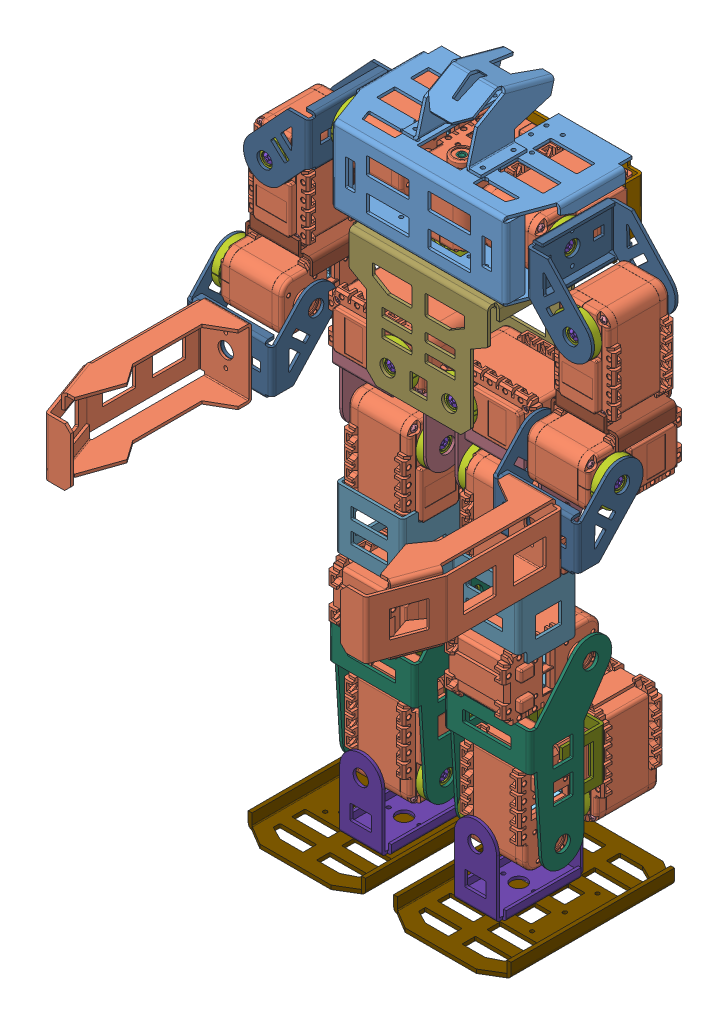
SolidWorks assembly BioloidGP2, configuration Default. Lengths in mm.
Overall size (259 352.56 195.51).
245 component instances, 20 part files, 109 mates.
Components (placement in the parent):
- FR04-E120-1: FR04-E120 [Default] at (-6.1822 -2.1819 114.2456) size (106 40.5 61.5)
- AX-12-18-A-2: AX-12-18-A [Default] at (31.961 8.8095 126.4932) x (0 1 0) z (1 0 0) size (32 50.04 40.18)
  - ASM0002_ASM-1: ASM0002_ASM [Default] at (-10.9914 -11.7476 -2.6432) size (32 50.04 40.18)
    - PRT0001-1: PRT0001 [Default] at origin size (32 50.04 38.06)
    - PRT0002-1: PRT0002 [Default] at (0 0 -2) x (-1 0 0) z (0 0 1) size (6.5 6.5 5.5)
    - PRT0003-1: PRT0003 [Default] at (9.5 8.5 14.5) x (-1 0 0) z (0 1 0) size (3.6 31.47 4.83)
    - PRT0003-2: PRT0003 [Default] at (-9.5 8.5 14.5) x (-1 0 0) z (0 1 0) size (3.6 31.47 4.83)
    - PRT0003-3: PRT0003 [Default] at (10.5 -33 14.5) x (-1 0 0) z (0 1 0) size (3.6 31.47 4.83)
    - PRT0003-4: PRT0003 [Default] at (-10.5 -33 14.5) x (-1 0 0) z (0 1 0) size (3.6 31.47 4.83)
    - PRT0004-1: PRT0004 [Default] at (5.05 -15.19 -9.75) x (1 0 0) z (0 1 0) size (9.9 9.43 4.9)
    - PRT0004-2: PRT0004 [Default] at (-4.95 -15.19 -9.75) x (1 0 0) z (0 1 0) size (9.9 9.43 4.9)
    - PRT0005-1: PRT0005 [Default] at (0 0 -18.4) x (-1 0 0) z (0 1 0) size (4.98 7 4.98)
    - PRT0006-1: PRT0006 [Default] at (0 0 19.16) x (0 1 0) z (0 0 1) size (22 22 6.7)
    - PRT0007-1: PRT0007 [Default] at (0 0 19.48) x (-1 0 0) z (0 1 0) size (5.5 9.69 5.91)
- AX-12-18-A-4: AX-12-18-A [Default] at (-44.3255 -13.1733 126.4932) x (0 -1 0) z (-1 0 0) size (32 50.04 40.18)
  - ASM0002_ASM-1: ASM0002_ASM [Default] at (-10.9914 -11.7476 -2.6432) size (32 50.04 40.18)
    - PRT0001-1: PRT0001 [Default] at origin size (32 50.04 38.06)
    - PRT0002-1: PRT0002 [Default] at (0 0 -2) x (-1 0 0) z (0 0 1) size (6.5 6.5 5.5)
    - PRT0003-1: PRT0003 [Default] at (9.5 8.5 14.5) x (-1 0 0) z (0 1 0) size (3.6 31.47 4.83)
    - PRT0003-2: PRT0003 [Default] at (-9.5 8.5 14.5) x (-1 0 0) z (0 1 0) size (3.6 31.47 4.83)
    - PRT0003-3: PRT0003 [Default] at (10.5 -33 14.5) x (-1 0 0) z (0 1 0) size (3.6 31.47 4.83)
    - PRT0003-4: PRT0003 [Default] at (-10.5 -33 14.5) x (-1 0 0) z (0 1 0) size (3.6 31.47 4.83)
    - PRT0004-1: PRT0004 [Default] at (5.05 -15.19 -9.75) x (1 0 0) z (0 1 0) size (9.9 9.43 4.9)
    - PRT0004-2: PRT0004 [Default] at (-4.95 -15.19 -9.75) x (1 0 0) z (0 1 0) size (9.9 9.43 4.9)
    - PRT0005-1: PRT0005 [Default] at (0 0 -18.4) x (-1 0 0) z (0 1 0) size (4.98 7 4.98)
    - PRT0006-1: PRT0006 [Default] at (0 0 19.16) x (0 1 0) z (0 0 1) size (22 22 6.7)
    - PRT0007-1: PRT0007 [Default] at (0 0 19.48) x (-1 0 0) z (0 1 0) size (5.5 9.69 5.91)
- FR04-E150-1: FR04-E150 [Default] at (-6.1822 -2.1819 115.0456) size (106 53 9.7)
- AX-12-18-A-6: AX-12-18-A [Default] at (4.8092 -10.3251 125.9932) x (1 0 0) z (0 -1 0) size (32 50.04 40.18)
  - ASM0002_ASM-1: ASM0002_ASM [Default] at (-10.9914 -11.7476 -2.6432) size (32 50.04 40.18)
    - PRT0001-1: PRT0001 [Default] at origin size (32 50.04 38.06)
    - PRT0002-1: PRT0002 [Default] at (0 0 -2) x (-1 0 0) z (0 0 1) size (6.5 6.5 5.5)
    - PRT0003-1: PRT0003 [Default] at (9.5 8.5 14.5) x (-1 0 0) z (0 1 0) size (3.6 31.47 4.83)
    - PRT0003-2: PRT0003 [Default] at (-9.5 8.5 14.5) x (-1 0 0) z (0 1 0) size (3.6 31.47 4.83)
    - PRT0003-3: PRT0003 [Default] at (10.5 -33 14.5) x (-1 0 0) z (0 1 0) size (3.6 31.47 4.83)
    - PRT0003-4: PRT0003 [Default] at (-10.5 -33 14.5) x (-1 0 0) z (0 1 0) size (3.6 31.47 4.83)
    - PRT0004-1: PRT0004 [Default] at (5.05 -15.19 -9.75) x (1 0 0) z (0 1 0) size (9.9 9.43 4.9)
    - PRT0004-2: PRT0004 [Default] at (-4.95 -15.19 -9.75) x (1 0 0) z (0 1 0) size (9.9 9.43 4.9)
    - PRT0005-1: PRT0005 [Default] at (0 0 -18.4) x (-1 0 0) z (0 1 0) size (4.98 7 4.98)
    - PRT0006-1: PRT0006 [Default] at (0 0 19.16) x (0 1 0) z (0 0 1) size (22 22 6.7)
    - PRT0007-1: PRT0007 [Default] at (0 0 19.48) x (-1 0 0) z (0 1 0) size (5.5 9.69 5.91)
- FR04-H102-1: FR04-H102 [Default] at (73.3178 -20.1819 114.7456) x (0 0 1) z (0 -1 0) size (45.02 34.01 42)
- FR04-H102-2: FR04-H102 [Default] at (-85.6822 -20.1819 114.7456) x (0 0 -1) z (0 -1 0) size (45.02 34.01 42)
- AX-12-18-A-7: AX-12-18-A [Default] at (84.3092 -8.4342 117.3888) size (32 50.04 40.18)
  - ASM0002_ASM-1: ASM0002_ASM [Default] at (-10.9914 -11.7476 -2.6432) size (32 50.04 40.18)
    - PRT0001-1: PRT0001 [Default] at origin size (32 50.04 38.06)
    - PRT0002-1: PRT0002 [Default] at (0 0 -2) x (-1 0 0) z (0 0 1) size (6.5 6.5 5.5)
    - PRT0003-1: PRT0003 [Default] at (9.5 8.5 14.5) x (-1 0 0) z (0 1 0) size (3.6 31.47 4.83)
    - PRT0003-2: PRT0003 [Default] at (-9.5 8.5 14.5) x (-1 0 0) z (0 1 0) size (3.6 31.47 4.83)
    - PRT0003-3: PRT0003 [Default] at (10.5 -33 14.5) x (-1 0 0) z (0 1 0) size (3.6 31.47 4.83)
    - PRT0003-4: PRT0003 [Default] at (-10.5 -33 14.5) x (-1 0 0) z (0 1 0) size (3.6 31.47 4.83)
    - PRT0004-1: PRT0004 [Default] at (5.05 -15.19 -9.75) x (1 0 0) z (0 1 0) size (9.9 9.43 4.9)
    - PRT0004-2: PRT0004 [Default] at (-4.95 -15.19 -9.75) x (1 0 0) z (0 1 0) size (9.9 9.43 4.9)
    - PRT0005-1: PRT0005 [Default] at (0 0 -18.4) x (-1 0 0) z (0 1 0) size (4.98 7 4.98)
    - PRT0006-1: PRT0006 [Default] at (0 0 19.16) x (0 1 0) z (0 0 1) size (22 22 6.7)
    - PRT0007-1: PRT0007 [Default] at (0 0 19.48) x (-1 0 0) z (0 1 0) size (5.5 9.69 5.91)
- AX-12-18-A-8: AX-12-18-A [Default] at (-74.6908 -8.4342 117.3888) size (32 50.04 40.18)
  - ASM0002_ASM-1: ASM0002_ASM [Default] at (-10.9914 -11.7476 -2.6432) size (32 50.04 40.18)
    - PRT0001-1: PRT0001 [Default] at origin size (32 50.04 38.06)
    - PRT0002-1: PRT0002 [Default] at (0 0 -2) x (-1 0 0) z (0 0 1) size (6.5 6.5 5.5)
    - PRT0003-1: PRT0003 [Default] at (9.5 8.5 14.5) x (-1 0 0) z (0 1 0) size (3.6 31.47 4.83)
    - PRT0003-2: PRT0003 [Default] at (-9.5 8.5 14.5) x (-1 0 0) z (0 1 0) size (3.6 31.47 4.83)
    - PRT0003-3: PRT0003 [Default] at (10.5 -33 14.5) x (-1 0 0) z (0 1 0) size (3.6 31.47 4.83)
    - PRT0003-4: PRT0003 [Default] at (-10.5 -33 14.5) x (-1 0 0) z (0 1 0) size (3.6 31.47 4.83)
    - PRT0004-1: PRT0004 [Default] at (5.05 -15.19 -9.75) x (1 0 0) z (0 1 0) size (9.9 9.43 4.9)
    - PRT0004-2: PRT0004 [Default] at (-4.95 -15.19 -9.75) x (1 0 0) z (0 1 0) size (9.9 9.43 4.9)
    - PRT0005-1: PRT0005 [Default] at (0 0 -18.4) x (-1 0 0) z (0 1 0) size (4.98 7 4.98)
    - PRT0006-1: PRT0006 [Default] at (0 0 19.16) x (0 1 0) z (0 0 1) size (22 22 6.7)
    - PRT0007-1: PRT0007 [Default] at (0 0 19.48) x (-1 0 0) z (0 1 0) size (5.5 9.69 5.91)
- AX-12-18-A-9: AX-12-18-A [Default] at (75.961 -66.5905 144.6932) x (0 1 0) z (1 0 0) size (32 50.04 40.18)
  - ASM0002_ASM-1: ASM0002_ASM [Default] at (-10.9914 -11.7476 -2.6432) size (32 50.04 40.18)
    - PRT0001-1: PRT0001 [Default] at origin size (32 50.04 38.06)
    - PRT0002-1: PRT0002 [Default] at (0 0 -2) x (-1 0 0) z (0 0 1) size (6.5 6.5 5.5)
    - PRT0003-1: PRT0003 [Default] at (9.5 8.5 14.5) x (-1 0 0) z (0 1 0) size (3.6 31.47 4.83)
    - PRT0003-2: PRT0003 [Default] at (-9.5 8.5 14.5) x (-1 0 0) z (0 1 0) size (3.6 31.47 4.83)
    - PRT0003-3: PRT0003 [Default] at (10.5 -33 14.5) x (-1 0 0) z (0 1 0) size (3.6 31.47 4.83)
    - PRT0003-4: PRT0003 [Default] at (-10.5 -33 14.5) x (-1 0 0) z (0 1 0) size (3.6 31.47 4.83)
    - PRT0004-1: PRT0004 [Default] at (5.05 -15.19 -9.75) x (1 0 0) z (0 1 0) size (9.9 9.43 4.9)
    - PRT0004-2: PRT0004 [Default] at (-4.95 -15.19 -9.75) x (1 0 0) z (0 1 0) size (9.9 9.43 4.9)
    - PRT0005-1: PRT0005 [Default] at (0 0 -18.4) x (-1 0 0) z (0 1 0) size (4.98 7 4.98)
    - PRT0006-1: PRT0006 [Default] at (0 0 19.16) x (0 1 0) z (0 0 1) size (22 22 6.7)
    - PRT0007-1: PRT0007 [Default] at (0 0 19.48) x (-1 0 0) z (0 1 0) size (5.5 9.69 5.91)
- AX-12-18-A-10: AX-12-18-A [Default] at (-88.3255 -88.5733 144.6932) x (0 -1 0) z (-1 0 0) size (32 50.04 40.18)
  - ASM0002_ASM-1: ASM0002_ASM [Default] at (-10.9914 -11.7476 -2.6432) size (32 50.04 40.18)
    - PRT0001-1: PRT0001 [Default] at origin size (32 50.04 38.06)
    - PRT0002-1: PRT0002 [Default] at (0 0 -2) x (-1 0 0) z (0 0 1) size (6.5 6.5 5.5)
    - PRT0003-1: PRT0003 [Default] at (9.5 8.5 14.5) x (-1 0 0) z (0 1 0) size (3.6 31.47 4.83)
    - PRT0003-2: PRT0003 [Default] at (-9.5 8.5 14.5) x (-1 0 0) z (0 1 0) size (3.6 31.47 4.83)
    - PRT0003-3: PRT0003 [Default] at (10.5 -33 14.5) x (-1 0 0) z (0 1 0) size (3.6 31.47 4.83)
    - PRT0003-4: PRT0003 [Default] at (-10.5 -33 14.5) x (-1 0 0) z (0 1 0) size (3.6 31.47 4.83)
    - PRT0004-1: PRT0004 [Default] at (5.05 -15.19 -9.75) x (1 0 0) z (0 1 0) size (9.9 9.43 4.9)
    - PRT0004-2: PRT0004 [Default] at (-4.95 -15.19 -9.75) x (1 0 0) z (0 1 0) size (9.9 9.43 4.9)
    - PRT0005-1: PRT0005 [Default] at (0 0 -18.4) x (-1 0 0) z (0 1 0) size (4.98 7 4.98)
    - PRT0006-1: PRT0006 [Default] at (0 0 19.16) x (0 1 0) z (0 0 1) size (22 22 6.7)
    - PRT0007-1: PRT0007 [Default] at (0 0 19.48) x (-1 0 0) z (0 1 0) size (5.5 9.69 5.91)
- FR04-SC101-3: FR04-SC101 [Default] at (-85.6822 -59.3819 114.7456) size (35 14.9 35)
- FR04-SC101-4: FR04-SC101 [Default] at (73.3178 -59.3819 114.7456) size (35 14.9 35)
- FR04-H102-3: FR04-H102 [Default] at (-85.6822 -77.5819 132.9456) x (-1 0 0) z (0 1 0) size (45.02 34.01 42)
- FR04-H102-4: FR04-H102 [Default] at (73.3178 -77.5819 132.9456) x (-1 0 0) z (0 1 0) size (45.02 34.01 42)
- FR04-E131-1: FR04-E131 [Default] at (-6.1822 -82.1819 114.2456) size (76 64.5 45)
- AX-12-18-A-11: AX-12-18-A [Default] at (-1.9298 -71.1905 116.8888) x (0 1 0) z (0 0 1) size (32 50.04 40.18)
  - ASM0002_ASM-1: ASM0002_ASM [Default] at (-10.9914 -11.7476 -2.6432) size (32 50.04 40.18)
    - PRT0001-1: PRT0001 [Default] at origin size (32 50.04 38.06)
    - PRT0002-1: PRT0002 [Default] at (0 0 -2) x (-1 0 0) z (0 0 1) size (6.5 6.5 5.5)
    - PRT0003-1: PRT0003 [Default] at (9.5 8.5 14.5) x (-1 0 0) z (0 1 0) size (3.6 31.47 4.83)
    - PRT0003-2: PRT0003 [Default] at (-9.5 8.5 14.5) x (-1 0 0) z (0 1 0) size (3.6 31.47 4.83)
    - PRT0003-3: PRT0003 [Default] at (10.5 -33 14.5) x (-1 0 0) z (0 1 0) size (3.6 31.47 4.83)
    - PRT0003-4: PRT0003 [Default] at (-10.5 -33 14.5) x (-1 0 0) z (0 1 0) size (3.6 31.47 4.83)
    - PRT0004-1: PRT0004 [Default] at (5.05 -15.19 -9.75) x (1 0 0) z (0 1 0) size (9.9 9.43 4.9)
    - PRT0004-2: PRT0004 [Default] at (-4.95 -15.19 -9.75) x (1 0 0) z (0 1 0) size (9.9 9.43 4.9)
    - PRT0005-1: PRT0005 [Default] at (0 0 -18.4) x (-1 0 0) z (0 1 0) size (4.98 7 4.98)
    - PRT0006-1: PRT0006 [Default] at (0 0 19.16) x (0 1 0) z (0 0 1) size (22 22 6.7)
    - PRT0007-1: PRT0007 [Default] at (0 0 19.48) x (-1 0 0) z (0 1 0) size (5.5 9.69 5.91)
- AX-12-18-A-13: AX-12-18-A [Default] at (-10.4346 -93.1733 116.8888) x (0 -1 0) z (0 0 1) size (32 50.04 40.18)
  - ASM0002_ASM-1: ASM0002_ASM [Default] at (-10.9914 -11.7476 -2.6432) size (32 50.04 40.18)
    - PRT0001-1: PRT0001 [Default] at origin size (32 50.04 38.06)
    - PRT0002-1: PRT0002 [Default] at (0 0 -2) x (-1 0 0) z (0 0 1) size (6.5 6.5 5.5)
    - PRT0003-1: PRT0003 [Default] at (9.5 8.5 14.5) x (-1 0 0) z (0 1 0) size (3.6 31.47 4.83)
    - PRT0003-2: PRT0003 [Default] at (-9.5 8.5 14.5) x (-1 0 0) z (0 1 0) size (3.6 31.47 4.83)
    - PRT0003-3: PRT0003 [Default] at (10.5 -33 14.5) x (-1 0 0) z (0 1 0) size (3.6 31.47 4.83)
    - PRT0003-4: PRT0003 [Default] at (-10.5 -33 14.5) x (-1 0 0) z (0 1 0) size (3.6 31.47 4.83)
    - PRT0004-1: PRT0004 [Default] at (5.05 -15.19 -9.75) x (1 0 0) z (0 1 0) size (9.9 9.43 4.9)
    - PRT0004-2: PRT0004 [Default] at (-4.95 -15.19 -9.75) x (1 0 0) z (0 1 0) size (9.9 9.43 4.9)
    - PRT0005-1: PRT0005 [Default] at (0 0 -18.4) x (-1 0 0) z (0 1 0) size (4.98 7 4.98)
    - PRT0006-1: PRT0006 [Default] at (0 0 19.16) x (0 1 0) z (0 0 1) size (22 22 6.7)
    - PRT0007-1: PRT0007 [Default] at (0 0 19.48) x (-1 0 0) z (0 1 0) size (5.5 9.69 5.91)
- FR04-HC110-1: FR04-HC110 [Default] at (-36.1822 -123.9819 114.2456) size (45 42.8 35)
- FR04-HC110-2: FR04-HC110 [Default] at (23.8178 -123.9819 114.2456) x (-1 0 0) z (0 0 -1) size (45 42.8 35)
- AX-12-18-A-16: AX-12-18-A [Default] at (21.1745 -112.2342 125.237) x (0 0 1) z (-1 0 0) size (32 50.04 40.18)
  - ASM0002_ASM-1: ASM0002_ASM [Default] at (-10.9914 -11.7476 -2.6432) size (32 50.04 40.18)
    - PRT0001-1: PRT0001 [Default] at origin size (32 50.04 38.06)
    - PRT0002-1: PRT0002 [Default] at (0 0 -2) x (-1 0 0) z (0 0 1) size (6.5 6.5 5.5)
    - PRT0003-1: PRT0003 [Default] at (9.5 8.5 14.5) x (-1 0 0) z (0 1 0) size (3.6 31.47 4.83)
    - PRT0003-2: PRT0003 [Default] at (-9.5 8.5 14.5) x (-1 0 0) z (0 1 0) size (3.6 31.47 4.83)
    - PRT0003-3: PRT0003 [Default] at (10.5 -33 14.5) x (-1 0 0) z (0 1 0) size (3.6 31.47 4.83)
    - PRT0003-4: PRT0003 [Default] at (-10.5 -33 14.5) x (-1 0 0) z (0 1 0) size (3.6 31.47 4.83)
    - PRT0004-1: PRT0004 [Default] at (5.05 -15.19 -9.75) x (1 0 0) z (0 1 0) size (9.9 9.43 4.9)
    - PRT0004-2: PRT0004 [Default] at (-4.95 -15.19 -9.75) x (1 0 0) z (0 1 0) size (9.9 9.43 4.9)
    - PRT0005-1: PRT0005 [Default] at (0 0 -18.4) x (-1 0 0) z (0 1 0) size (4.98 7 4.98)
    - PRT0006-1: PRT0006 [Default] at (0 0 19.16) x (0 1 0) z (0 0 1) size (22 22 6.7)
    - PRT0007-1: PRT0007 [Default] at (0 0 19.48) x (-1 0 0) z (0 1 0) size (5.5 9.69 5.91)
- AX-12-18-A-17: AX-12-18-A [Default] at (-33.539 -112.2342 103.2542) x (0 0 -1) z (1 0 0) size (32 50.04 40.18)
  - ASM0002_ASM-1: ASM0002_ASM [Default] at (-10.9914 -11.7476 -2.6432) size (32 50.04 40.18)
    - PRT0001-1: PRT0001 [Default] at origin size (32 50.04 38.06)
    - PRT0002-1: PRT0002 [Default] at (0 0 -2) x (-1 0 0) z (0 0 1) size (6.5 6.5 5.5)
    - PRT0003-1: PRT0003 [Default] at (9.5 8.5 14.5) x (-1 0 0) z (0 1 0) size (3.6 31.47 4.83)
    - PRT0003-2: PRT0003 [Default] at (-9.5 8.5 14.5) x (-1 0 0) z (0 1 0) size (3.6 31.47 4.83)
    - PRT0003-3: PRT0003 [Default] at (10.5 -33 14.5) x (-1 0 0) z (0 1 0) size (3.6 31.47 4.83)
    - PRT0003-4: PRT0003 [Default] at (-10.5 -33 14.5) x (-1 0 0) z (0 1 0) size (3.6 31.47 4.83)
    - PRT0004-1: PRT0004 [Default] at (5.05 -15.19 -9.75) x (1 0 0) z (0 1 0) size (9.9 9.43 4.9)
    - PRT0004-2: PRT0004 [Default] at (-4.95 -15.19 -9.75) x (1 0 0) z (0 1 0) size (9.9 9.43 4.9)
    - PRT0005-1: PRT0005 [Default] at (0 0 -18.4) x (-1 0 0) z (0 1 0) size (4.98 7 4.98)
    - PRT0006-1: PRT0006 [Default] at (0 0 19.16) x (0 1 0) z (0 0 1) size (22 22 6.7)
    - PRT0007-1: PRT0007 [Default] at (0 0 19.48) x (-1 0 0) z (0 1 0) size (5.5 9.69 5.91)
- FR04-SC110-1: FR04-SC110 [Default] at (-36.1822 -123.6819 113.9456) size (35 37.2 29.5)
- FR04-SC110-2: FR04-SC110 [Default] at (23.8178 -123.6819 113.9456) size (35 37.2 29.5)
- AX-12-18-A-18: AX-12-18-A [Default] at (21.1745 -187.3905 87.9979) x (0 1 0) z (-1 0 0) size (32 50.04 40.18)
  - ASM0002_ASM-1: ASM0002_ASM [Default] at (-10.9914 -11.7476 -2.6432) size (32 50.04 40.18)
    - PRT0001-1: PRT0001 [Default] at origin size (32 50.04 38.06)
    - PRT0002-1: PRT0002 [Default] at (0 0 -2) x (-1 0 0) z (0 0 1) size (6.5 6.5 5.5)
    - PRT0003-1: PRT0003 [Default] at (9.5 8.5 14.5) x (-1 0 0) z (0 1 0) size (3.6 31.47 4.83)
    - PRT0003-2: PRT0003 [Default] at (-9.5 8.5 14.5) x (-1 0 0) z (0 1 0) size (3.6 31.47 4.83)
    - PRT0003-3: PRT0003 [Default] at (10.5 -33 14.5) x (-1 0 0) z (0 1 0) size (3.6 31.47 4.83)
    - PRT0003-4: PRT0003 [Default] at (-10.5 -33 14.5) x (-1 0 0) z (0 1 0) size (3.6 31.47 4.83)
    - PRT0004-1: PRT0004 [Default] at (5.05 -15.19 -9.75) x (1 0 0) z (0 1 0) size (9.9 9.43 4.9)
    - PRT0004-2: PRT0004 [Default] at (-4.95 -15.19 -9.75) x (1 0 0) z (0 1 0) size (9.9 9.43 4.9)
    - PRT0005-1: PRT0005 [Default] at (0 0 -18.4) x (-1 0 0) z (0 1 0) size (4.98 7 4.98)
    - PRT0006-1: PRT0006 [Default] at (0 0 19.16) x (0 1 0) z (0 0 1) size (22 22 6.7)
    - PRT0007-1: PRT0007 [Default] at (0 0 19.48) x (-1 0 0) z (0 1 0) size (5.5 9.69 5.91)
- AX-12-18-A-19: AX-12-18-A [Default] at (-33.539 -209.3733 87.9979) x (0 -1 0) z (1 0 0) size (32 50.04 40.18)
  - ASM0002_ASM-1: ASM0002_ASM [Default] at (-10.9914 -11.7476 -2.6432) size (32 50.04 40.18)
    - PRT0001-1: PRT0001 [Default] at origin size (32 50.04 38.06)
    - PRT0002-1: PRT0002 [Default] at (0 0 -2) x (-1 0 0) z (0 0 1) size (6.5 6.5 5.5)
    - PRT0003-1: PRT0003 [Default] at (9.5 8.5 14.5) x (-1 0 0) z (0 1 0) size (3.6 31.47 4.83)
    - PRT0003-2: PRT0003 [Default] at (-9.5 8.5 14.5) x (-1 0 0) z (0 1 0) size (3.6 31.47 4.83)
    - PRT0003-3: PRT0003 [Default] at (10.5 -33 14.5) x (-1 0 0) z (0 1 0) size (3.6 31.47 4.83)
    - PRT0003-4: PRT0003 [Default] at (-10.5 -33 14.5) x (-1 0 0) z (0 1 0) size (3.6 31.47 4.83)
    - PRT0004-1: PRT0004 [Default] at (5.05 -15.19 -9.75) x (1 0 0) z (0 1 0) size (9.9 9.43 4.9)
    - PRT0004-2: PRT0004 [Default] at (-4.95 -15.19 -9.75) x (1 0 0) z (0 1 0) size (9.9 9.43 4.9)
    - PRT0005-1: PRT0005 [Default] at (0 0 -18.4) x (-1 0 0) z (0 1 0) size (4.98 7 4.98)
    - PRT0006-1: PRT0006 [Default] at (0 0 19.16) x (0 1 0) z (0 0 1) size (22 22 6.7)
    - PRT0007-1: PRT0007 [Default] at (0 0 19.48) x (-1 0 0) z (0 1 0) size (5.5 9.69 5.91)
- FR04-H120-1: FR04-H120 [Default] at (-36.1822 -273.3819 114.2456) x (-1 0 0) z (0 0 1) size (45 97 42.5)
- FR04-H120-2: FR04-H120 [Default] at (23.8178 -273.3819 114.2456) x (-1 0 0) z (0 0 1) size (45 97 42.5)
- AX-12-18-A-20: AX-12-18-A [Default] at (-33.539 -285.1295 125.237) x (0 0 1) z (1 0 0) size (32 50.04 40.18)
  - ASM0002_ASM-1: ASM0002_ASM [Default] at (-10.9914 -11.7476 -2.6432) size (32 50.04 40.18)
    - PRT0001-1: PRT0001 [Default] at origin size (32 50.04 38.06)
    - PRT0002-1: PRT0002 [Default] at (0 0 -2) x (-1 0 0) z (0 0 1) size (6.5 6.5 5.5)
    - PRT0003-1: PRT0003 [Default] at (9.5 8.5 14.5) x (-1 0 0) z (0 1 0) size (3.6 31.47 4.83)
    - PRT0003-2: PRT0003 [Default] at (-9.5 8.5 14.5) x (-1 0 0) z (0 1 0) size (3.6 31.47 4.83)
    - PRT0003-3: PRT0003 [Default] at (10.5 -33 14.5) x (-1 0 0) z (0 1 0) size (3.6 31.47 4.83)
    - PRT0003-4: PRT0003 [Default] at (-10.5 -33 14.5) x (-1 0 0) z (0 1 0) size (3.6 31.47 4.83)
    - PRT0004-1: PRT0004 [Default] at (5.05 -15.19 -9.75) x (1 0 0) z (0 1 0) size (9.9 9.43 4.9)
    - PRT0004-2: PRT0004 [Default] at (-4.95 -15.19 -9.75) x (1 0 0) z (0 1 0) size (9.9 9.43 4.9)
    - PRT0005-1: PRT0005 [Default] at (0 0 -18.4) x (-1 0 0) z (0 1 0) size (4.98 7 4.98)
    - PRT0006-1: PRT0006 [Default] at (0 0 19.16) x (0 1 0) z (0 0 1) size (22 22 6.7)
    - PRT0007-1: PRT0007 [Default] at (0 0 19.48) x (-1 0 0) z (0 1 0) size (5.5 9.69 5.91)
- AX-12-18-A-21: AX-12-18-A [Default] at (21.1745 -285.1295 103.2542) x (0 0 -1) z (-1 0 0) size (32 50.04 40.18)
  - ASM0002_ASM-1: ASM0002_ASM [Default] at (-10.9914 -11.7476 -2.6432) size (32 50.04 40.18)
    - PRT0001-1: PRT0001 [Default] at origin size (32 50.04 38.06)
    - PRT0002-1: PRT0002 [Default] at (0 0 -2) x (-1 0 0) z (0 0 1) size (6.5 6.5 5.5)
    - PRT0003-1: PRT0003 [Default] at (9.5 8.5 14.5) x (-1 0 0) z (0 1 0) size (3.6 31.47 4.83)
    - PRT0003-2: PRT0003 [Default] at (-9.5 8.5 14.5) x (-1 0 0) z (0 1 0) size (3.6 31.47 4.83)
    - PRT0003-3: PRT0003 [Default] at (10.5 -33 14.5) x (-1 0 0) z (0 1 0) size (3.6 31.47 4.83)
    - PRT0003-4: PRT0003 [Default] at (-10.5 -33 14.5) x (-1 0 0) z (0 1 0) size (3.6 31.47 4.83)
    - PRT0004-1: PRT0004 [Default] at (5.05 -15.19 -9.75) x (1 0 0) z (0 1 0) size (9.9 9.43 4.9)
    - PRT0004-2: PRT0004 [Default] at (-4.95 -15.19 -9.75) x (1 0 0) z (0 1 0) size (9.9 9.43 4.9)
    - PRT0005-1: PRT0005 [Default] at (0 0 -18.4) x (-1 0 0) z (0 1 0) size (4.98 7 4.98)
    - PRT0006-1: PRT0006 [Default] at (0 0 19.16) x (0 1 0) z (0 0 1) size (22 22 6.7)
    - PRT0007-1: PRT0007 [Default] at (0 0 19.48) x (-1 0 0) z (0 1 0) size (5.5 9.69 5.91)
- FR04-X101-1: FR04-X101 [Default] at (-36.1822 -251.1819 100.9456) x (1 0 0) z (0 1 0) size (35 22.5 26.5)
- FR04-X101-2: FR04-X101 [Default] at (23.8178 -251.1819 100.9456) x (1 0 0) z (0 1 0) size (35 22.5 26.5)
- AX-12-18-A-22: AX-12-18-A [Default] at (-46.9736 -285.2295 73.5888) x (-1 0 0) z (0 0 1) size (32 50.04 40.18)
  - ASM0002_ASM-1: ASM0002_ASM [Default] at (-10.9914 -11.7476 -2.6432) size (32 50.04 40.18)
    - PRT0001-1: PRT0001 [Default] at origin size (32 50.04 38.06)
    - PRT0002-1: PRT0002 [Default] at (0 0 -2) x (-1 0 0) z (0 0 1) size (6.5 6.5 5.5)
    - PRT0003-1: PRT0003 [Default] at (9.5 8.5 14.5) x (-1 0 0) z (0 1 0) size (3.6 31.47 4.83)
    - PRT0003-2: PRT0003 [Default] at (-9.5 8.5 14.5) x (-1 0 0) z (0 1 0) size (3.6 31.47 4.83)
    - PRT0003-3: PRT0003 [Default] at (10.5 -33 14.5) x (-1 0 0) z (0 1 0) size (3.6 31.47 4.83)
    - PRT0003-4: PRT0003 [Default] at (-10.5 -33 14.5) x (-1 0 0) z (0 1 0) size (3.6 31.47 4.83)
    - PRT0004-1: PRT0004 [Default] at (5.05 -15.19 -9.75) x (1 0 0) z (0 1 0) size (9.9 9.43 4.9)
    - PRT0004-2: PRT0004 [Default] at (-4.95 -15.19 -9.75) x (1 0 0) z (0 1 0) size (9.9 9.43 4.9)
    - PRT0005-1: PRT0005 [Default] at (0 0 -18.4) x (-1 0 0) z (0 1 0) size (4.98 7 4.98)
    - PRT0006-1: PRT0006 [Default] at (0 0 19.16) x (0 1 0) z (0 0 1) size (22 22 6.7)
    - PRT0007-1: PRT0007 [Default] at (0 0 19.48) x (-1 0 0) z (0 1 0) size (5.5 9.69 5.91)
- AX-12-18-A-23: AX-12-18-A [Default] at (12.6264 -285.2295 73.5888) x (-1 0 0) z (0 0 1) size (32 50.04 40.18)
  - ASM0002_ASM-1: ASM0002_ASM [Default] at (-10.9914 -11.7476 -2.6432) size (32 50.04 40.18)
    - PRT0001-1: PRT0001 [Default] at origin size (32 50.04 38.06)
    - PRT0002-1: PRT0002 [Default] at (0 0 -2) x (-1 0 0) z (0 0 1) size (6.5 6.5 5.5)
    - PRT0003-1: PRT0003 [Default] at (9.5 8.5 14.5) x (-1 0 0) z (0 1 0) size (3.6 31.47 4.83)
    - PRT0003-2: PRT0003 [Default] at (-9.5 8.5 14.5) x (-1 0 0) z (0 1 0) size (3.6 31.47 4.83)
    - PRT0003-3: PRT0003 [Default] at (10.5 -33 14.5) x (-1 0 0) z (0 1 0) size (3.6 31.47 4.83)
    - PRT0003-4: PRT0003 [Default] at (-10.5 -33 14.5) x (-1 0 0) z (0 1 0) size (3.6 31.47 4.83)
    - PRT0004-1: PRT0004 [Default] at (5.05 -15.19 -9.75) x (1 0 0) z (0 1 0) size (9.9 9.43 4.9)
    - PRT0004-2: PRT0004 [Default] at (-4.95 -15.19 -9.75) x (1 0 0) z (0 1 0) size (9.9 9.43 4.9)
    - PRT0005-1: PRT0005 [Default] at (0 0 -18.4) x (-1 0 0) z (0 1 0) size (4.98 7 4.98)
    - PRT0006-1: PRT0006 [Default] at (0 0 19.16) x (0 1 0) z (0 0 1) size (22 22 6.7)
    - PRT0007-1: PRT0007 [Default] at (0 0 19.48) x (-1 0 0) z (0 1 0) size (5.5 9.69 5.91)
- FR04-H101-1: FR04-H101 [Default] at (-35.9822 -273.4819 114.4456) x (0 0 1) z (1 0 0) size (45 41 26)
- FR04-H101-2: FR04-H101 [Default] at (23.6178 -273.4819 114.4456) x (0 0 -1) z (-1 0 0) size (45 41 26)
- FR04-E160-1: FR04-E160 [Default] at (-43.9822 -303.4819 114.4456) size (61 8 97)
- FR04-E160-2: FR04-E160 [Default] at (31.6178 -303.4819 114.4456) size (61 8 97)
- FR04-E175-1: FR04-E175 [Default] at (-6.1822 15.3181 124.7294) x (1 0 0) z (0 0.258819 0.965926) size (41 31.63 43.12)
- FR04-E180-1: FR04-E180 [Default] at (-85.6822 -95.5819 155.9456) x (1 0 0) z (0 1 0) size (27 91.51 36)
- FR04-E180-2: FR04-E180 [Default] at (73.3178 -95.5819 155.9456) x (-1 0 0) z (0 -1 0) size (27 91.51 36)
Mates (geometry in assembly coordinates):
- Coincident2: coincident anti-aligned: plane of FR04-E120-1 through (45.3178 -2.1819 114.2456) normal (-1 0 0); plane of AX-12-18-A-2/ASM0002_ASM-1/PRT0001-1 through (45.3178 -2.1819 114.7456) normal (1 0 0)
- Coincident4: coincident anti-aligned: plane of FR04-E120-1 through (-59.2222 13.8181 135.9356) normal (0 -1 0); plane of AX-12-18-A-2/ASM0002_ASM-1/PRT0001-1 through (45.3178 13.8181 112.7456) normal (0 1 0)
- Coincident6: coincident anti-aligned: plane of FR04-E120-1 through (-57.6822 -2.1819 114.2456) normal (1 0 0); plane of AX-12-18-A-4/ASM0002_ASM-1/PRT0001-1 through (-57.6822 -2.1819 114.7456) normal (-1 0 0)
- Coincident7: coincident anti-aligned: plane of FR04-E120-1 through (-59.2222 13.8181 135.9356) normal (0 -1 0); plane of AX-12-18-A-4/ASM0002_ASM-1/PRT0001-1 through (-57.6822 13.8181 79.7456) normal (0 1 0)
- Coincident8: coincident anti-aligned: plane of FR04-E120-1 through (-59.2222 13.8181 135.9356) normal (0 -1 0); plane of FR04-E150-1 through (-6.1822 13.8181 115.0456) normal (0 1 0)
- Coincident9: coincident anti-aligned: plane of FR04-E120-1 through (-59.2222 -23.6819 74.0556) normal (0 1 0); plane of AX-12-18-A-6/ASM0002_ASM-1/PRT0001-1 through (-6.1822 -23.6819 114.2456) normal (0 -1 0)
- Coincident10: coincident anti-aligned: plane of FR04-E120-1 through (-6.1822 -2.1819 82.2456) normal (0 0 -1); plane of FR04-E150-1 through (-6.1822 -2.1819 82.2456) normal (0 0 1)
- Coincident11: coincident aligned: plane of FR04-E120-1 through (46.8178 -2.1819 114.2456) normal (1 0 0); plane of FR04-E150-1 through (46.8178 8.0181 82.2456) normal (1 0 0)
- Coincident12: coincident anti-aligned: plane of AX-12-18-A-2/ASM0002_ASM-1/PRT0001-1 through (48.3178 7.8181 82.2456) normal (0 0 -1); plane of FR04-E150-1 through (-6.1822 -2.1819 82.2456) normal (0 0 1)
- Coincident13: coincident anti-aligned: plane of AX-12-18-A-4/ASM0002_ASM-1/PRT0001-1 through (-60.6822 -12.1819 82.2456) normal (0 0 -1); plane of FR04-E150-1 through (-6.1822 -2.1819 82.2456) normal (0 0 1)
- Coincident14: coincident anti-aligned: plane of AX-12-18-A-2/ASM0002_ASM-1/PRT0006-1 through (50.3178 -2.1819 114.7456) normal (1 0 0); plane of FR04-H102-1 through (50.3178 9.7781 93.4256) normal (-1 0 0)
- Concentric1: concentric aligned: cylinder of AX-12-18-A-2/ASM0002_ASM-1/PRT0006-1 through (51.1778 -2.1819 114.7456) axis (1 0 0) radius 2.9; cylinder of FR04-H102-1 through (51.8178 -2.1819 114.7456) axis (1 0 0) radius 4
- Coincident15: coincident anti-aligned: plane of AX-12-18-A-4/ASM0002_ASM-1/PRT0006-1 through (-62.6822 -2.1819 114.7456) normal (-1 0 0); plane of FR04-H102-2 through (-62.6822 9.7781 136.0656) normal (1 0 0)
- Concentric2: concentric aligned: cylinder of AX-12-18-A-4/ASM0002_ASM-1/PRT0006-1 through (-63.5422 -2.1819 114.7456) axis (-1 0 0) radius 2.9; cylinder of FR04-H102-2 through (-64.1822 -2.1819 114.7456) axis (-1 0 0) radius 4
- Coincident16: coincident anti-aligned: plane of FR04-H102-1 through (51.6778 9.6181 135.7456) normal (0 0 -1); plane of AX-12-18-A-7/ASM0002_ASM-1/PRT0006-1 through (73.3178 -20.1819 135.7456) normal (0 0 1)
- Concentric3: concentric anti-aligned: cylinder of FR04-H102-1 through (73.3178 -20.1819 135.7456) axis (0 0 -1) radius 4; cylinder of AX-12-18-A-7/ASM0002_ASM-1/PRT0006-1 through (73.3178 -20.1819 136.6056) axis (0 0 1) radius 2.9
- Coincident18: coincident anti-aligned: plane of FR04-H102-2 through (-97.3232 9.6181 135.7456) normal (0 0 -1); plane of AX-12-18-A-8/ASM0002_ASM-1/PRT0006-1 through (-85.6822 -20.1819 135.7456) normal (0 0 1)
- Concentric4: concentric anti-aligned: cylinder of FR04-H102-2 through (-85.6822 -20.1819 135.7456) axis (0 0 -1) radius 4; cylinder of AX-12-18-A-8/ASM0002_ASM-1/PRT0006-1 through (-85.6822 -20.1819 136.6056) axis (0 0 1) radius 2.9
- Coincident19: coincident anti-aligned: plane of AX-12-18-A-7/ASM0002_ASM-1/PRT0001-1 through (73.3178 -20.1819 130.7456) normal (0 0 1); plane of FR04-SC101-4 through (60.8178 -52.6819 130.7456) normal (0 0 -1)
- Coincident20: coincident anti-aligned: plane of AX-12-18-A-8/ASM0002_ASM-1/PRT0001-1 through (-85.6822 -20.1819 130.7456) normal (0 0 1); plane of FR04-SC101-3 through (-98.1822 -52.6819 130.7456) normal (0 0 -1)
- Coincident21: coincident anti-aligned: plane of AX-12-18-A-7/ASM0002_ASM-1/PRT0001-1 through (83.3178 -52.6819 133.7456) normal (0 -1 0); plane of FR04-SC101-4 through (73.3178 -52.6819 114.7456) normal (0 1 0)
- Coincident22: coincident anti-aligned: plane of AX-12-18-A-8/ASM0002_ASM-1/PRT0001-1 through (-75.6822 -52.6819 133.7456) normal (0 -1 0); plane of FR04-SC101-3 through (-85.6822 -52.6819 114.7456) normal (0 1 0)
- Coincident23: coincident aligned: plane of AX-12-18-A-7/ASM0002_ASM-1/PRT0001-1 through (60.8178 -58.6819 130.7456) normal (-1 0 0); plane of FR04-SC101-4 through (60.8178 -60.8819 97.2456) normal (-1 0 0)
- Coincident24: coincident aligned: plane of AX-12-18-A-8/ASM0002_ASM-1/PRT0001-1 through (-73.1822 -55.6819 130.7456) normal (1 0 0); plane of FR04-SC101-3 through (-73.1822 -60.8819 132.2456) normal (1 0 0)
- Coincident25: coincident anti-aligned: plane of AX-12-18-A-9/ASM0002_ASM-1/PRT0001-1 through (89.3178 -77.5819 132.9456) normal (1 0 0); plane of FR04-SC101-4 through (89.3178 -67.5819 99.7456) normal (-1 0 0)
- Coincident26: coincident anti-aligned: plane of AX-12-18-A-9/ASM0002_ASM-1/PRT0001-1 through (92.3178 -67.5819 144.4456) normal (0 1 0); plane of FR04-SC101-4 through (73.3178 -67.5819 114.7456) normal (0 -1 0)
- Coincident28: coincident aligned: plane of AX-12-18-A-9/ASM0002_ASM-1/PRT0001-1 through (89.3178 -93.5819 129.7456) normal (0 0 1); plane of FR04-SC101-4 through (90.8178 -60.8819 129.7456) normal (0 0 1)
- Coincident29: coincident anti-aligned: plane of AX-12-18-A-10/ASM0002_ASM-1/PRT0001-1 through (-101.6822 -77.5819 132.9456) normal (-1 0 0); plane of FR04-SC101-3 through (-101.6822 -67.5819 129.7456) normal (1 0 0)
- Coincident30: coincident anti-aligned: plane of AX-12-18-A-10/ASM0002_ASM-1/PRT0001-1 through (-104.6822 -67.5819 100.4456) normal (0 1 0); plane of FR04-SC101-3 through (-85.6822 -67.5819 114.7456) normal (0 -1 0)
- Coincident31: coincident aligned: plane of AX-12-18-A-10/ASM0002_ASM-1/PRT0001-1 through (-101.6822 -61.5819 129.7456) normal (0 0 1); plane of FR04-SC101-3 through (-103.1822 -59.3819 129.7456) normal (0 0 1)
- Coincident32: coincident anti-aligned: plane of AX-12-18-A-9/ASM0002_ASM-1/PRT0006-1 through (94.3178 -77.5819 132.9456) normal (1 0 0); plane of FR04-H102-4 through (94.3178 -107.3819 121.3046) normal (-1 0 0)
- Concentric5: concentric anti-aligned: cylinder of AX-12-18-A-9/ASM0002_ASM-1/PRT0006-1 through (95.1778 -77.5819 132.9456) axis (1 0 0) radius 2.9; cylinder of FR04-H102-4 through (94.3178 -77.5819 132.9456) axis (-1 0 0) radius 4
- Coincident33: coincident anti-aligned: plane of AX-12-18-A-10/ASM0002_ASM-1/PRT0006-1 through (-106.6822 -77.5819 132.9456) normal (-1 0 0); plane of FR04-H102-3 through (-106.6822 -107.3819 154.5856) normal (1 0 0)
- Concentric6: concentric anti-aligned: cylinder of AX-12-18-A-10/ASM0002_ASM-1/PRT0006-1 through (-107.5422 -77.5819 132.9456) axis (-1 0 0) radius 2.9; cylinder of FR04-H102-3 through (-106.6822 -77.5819 132.9456) axis (1 0 0) radius 4
- Concentric7: concentric anti-aligned: cylinder of AX-12-18-A-6/ASM0002_ASM-1/PRT0006-1 through (-6.1822 -29.5419 114.2456) axis (0 -1 0) radius 2.9; cylinder of FR04-E131-1 through (-6.1822 -28.6819 114.2456) axis (0 1 0) radius 4
- Coincident34: coincident anti-aligned: plane of AX-12-18-A-6/ASM0002_ASM-1/PRT0006-1 through (-6.1822 -28.6819 114.2456) normal (0 -1 0); plane of FR04-E131-1 through (-6.1822 -28.6819 114.2456) normal (0 1 0)
- Coincident37: coincident anti-aligned: plane of FR04-E131-1 through (29.8178 -93.1819 135.2456) normal (0 0 -1); plane of AX-12-18-A-11/ASM0002_ASM-1/PRT0006-1 through (9.8178 -82.1819 135.2456) normal (0 0 1)
- Coincident38: coincident anti-aligned: plane of FR04-E131-1 through (29.8178 -93.1819 135.2456) normal (0 0 -1); plane of AX-12-18-A-13/ASM0002_ASM-1/PRT0006-1 through (-22.1822 -82.1819 135.2456) normal (0 0 1)
- Concentric10: concentric anti-aligned: cylinder of FR04-E131-1 through (9.8178 -82.1819 135.2456) axis (0 0 -1) radius 4; cylinder of AX-12-18-A-11/ASM0002_ASM-1/PRT0006-1 through (9.8178 -82.1819 136.1056) axis (0 0 1) radius 2.9
- Concentric11: concentric anti-aligned: cylinder of FR04-E131-1 through (-22.1822 -82.1819 135.2456) axis (0 0 -1) radius 4; cylinder of AX-12-18-A-13/ASM0002_ASM-1/PRT0006-1 through (-22.1822 -82.1819 136.1056) axis (0 0 1) radius 2.9
- Coincident39: coincident anti-aligned: plane of AX-12-18-A-13/ASM0002_ASM-1/PRT0001-1 through (-22.1822 -82.1819 130.2456) normal (0 0 1); plane of FR04-HC110-1 through (-55.9822 -92.1819 130.2456) normal (0 0 -1)
- Coincident40: coincident anti-aligned: plane of AX-12-18-A-11/ASM0002_ASM-1/PRT0001-1 through (9.8178 -82.1819 130.2456) normal (0 0 1); plane of FR04-HC110-2 through (13.0178 -92.1819 130.2456) normal (0 0 -1)
- Coincident41: coincident aligned: plane of AX-12-18-A-11/ASM0002_ASM-1/PRT0001-1 through (43.6178 -96.6819 130.2456) normal (1 0 0); plane of FR04-HC110-2 through (43.6178 -98.4819 131.7456) normal (1 0 0)
- Coincident42: coincident aligned: plane of AX-12-18-A-13/ASM0002_ASM-1/PRT0001-1 through (-55.9822 -96.6819 130.2456) normal (-1 0 0); plane of FR04-HC110-1 through (-55.9822 -99.9819 131.7456) normal (-1 0 0)
- Coincident43: coincident anti-aligned: plane of AX-12-18-A-13/ASM0002_ASM-1/PRT0001-1 through (-10.6822 -92.1819 133.2456) normal (0 -1 0); plane of FR04-HC110-1 through (-36.1822 -92.1819 114.2456) normal (0 1 0)
- Coincident44: coincident anti-aligned: plane of AX-12-18-A-11/ASM0002_ASM-1/PRT0001-1 through (42.3178 -92.1819 133.2456) normal (0 -1 0); plane of FR04-HC110-2 through (23.8178 -92.1819 114.2456) normal (0 1 0)
- Coincident45: coincident anti-aligned: plane of FR04-HC110-1 through (-15.1822 -141.8645 103.2456) normal (-1 0 0); plane of AX-12-18-A-17/ASM0002_ASM-1/PRT0006-1 through (-15.1822 -123.9819 114.2456) normal (1 0 0)
- Concentric12: concentric anti-aligned: cylinder of FR04-HC110-1 through (-15.1822 -123.9819 114.2456) axis (-1 0 0) radius 4; cylinder of AX-12-18-A-17/ASM0002_ASM-1/PRT0006-1 through (-14.3222 -123.9819 114.2456) axis (1 0 0) radius 2.9
- Coincident46: coincident anti-aligned: plane of FR04-HC110-2 through (2.8178 -141.8645 125.2456) normal (1 0 0); plane of AX-12-18-A-16/ASM0002_ASM-1/PRT0006-1 through (2.8178 -123.9819 114.2456) normal (-1 0 0)
- Concentric13: concentric anti-aligned: cylinder of FR04-HC110-2 through (2.8178 -123.9819 114.2456) axis (1 0 0) radius 4; cylinder of AX-12-18-A-16/ASM0002_ASM-1/PRT0006-1 through (1.9578 -123.9819 114.2456) axis (-1 0 0) radius 2.9
- Coincident47: coincident anti-aligned: plane of AX-12-18-A-17/ASM0002_ASM-1/PRT0001-1 through (-20.1822 -123.9819 114.2456) normal (1 0 0); plane of FR04-SC110-1 through (-20.1822 -123.6819 113.9456) normal (-1 0 0)
- Coincident48: coincident anti-aligned: plane of AX-12-18-A-16/ASM0002_ASM-1/PRT0001-1 through (7.8178 -123.9819 114.2456) normal (-1 0 0); plane of FR04-SC110-2 through (7.8178 -182.3819 102.9456) normal (1 0 0)
- Coincident49: coincident anti-aligned: plane of AX-12-18-A-16/ASM0002_ASM-1/PRT0001-1 through (4.8178 -112.4819 124.2456) normal (0 0 1); plane of FR04-SC110-2 through (41.3178 -156.4819 124.2456) normal (0 0 -1)
- Coincident50: coincident anti-aligned: plane of AX-12-18-A-16/ASM0002_ASM-1/PRT0001-1 through (4.8178 -156.4819 124.2456) normal (0 -1 0); plane of FR04-SC110-2 through (41.3178 -156.4819 102.9456) normal (0 1 0)
- Coincident51: coincident anti-aligned: plane of AX-12-18-A-17/ASM0002_ASM-1/PRT0001-1 through (-17.1822 -156.4819 104.2456) normal (0 -1 0); plane of FR04-SC110-1 through (-53.6832 -156.4819 124.2456) normal (0 1 0)
- Coincident52: coincident anti-aligned: plane of AX-12-18-A-17/ASM0002_ASM-1/PRT0001-1 through (-17.1822 -156.4819 124.2456) normal (0 0 1); plane of FR04-SC110-1 through (-53.6832 -151.1819 124.2456) normal (0 0 -1)
- Coincident53: coincident anti-aligned: plane of FR04-SC110-1 through (-18.6822 -188.3819 102.9456) normal (0 -1 0); plane of AX-12-18-A-19/ASM0002_ASM-1/PRT0001-1 through (-17.1822 -188.3819 132.2456) normal (0 1 0)
- Coincident54: coincident anti-aligned: plane of FR04-SC110-2 through (23.8178 -188.3819 113.9456) normal (0 -1 0); plane of AX-12-18-A-18/ASM0002_ASM-1/PRT0001-1 through (4.8178 -188.3819 88.2456) normal (0 1 0)
- Coincident55: coincident anti-aligned: plane of FR04-SC110-1 through (-20.1822 -123.6819 113.9456) normal (-1 0 0); plane of AX-12-18-A-19/ASM0002_ASM-1/PRT0001-1 through (-20.1822 -198.3819 99.7456) normal (1 0 0)
- Coincident56: coincident anti-aligned: plane of FR04-SC110-2 through (7.8178 -182.3819 102.9456) normal (1 0 0); plane of AX-12-18-A-18/ASM0002_ASM-1/PRT0001-1 through (7.8178 -198.3819 99.7456) normal (-1 0 0)
- Coincident57: coincident aligned: plane of FR04-SC110-1 through (-18.6822 -151.1819 102.9456) normal (0 0 -1); plane of AX-12-18-A-19/ASM0002_ASM-1/PRT0001-1 through (-20.1822 -182.3819 102.9456) normal (0 0 -1)
- Coincident58: coincident aligned: plane of FR04-SC110-2 through (23.8178 -123.6819 102.9456) normal (0 0 -1); plane of AX-12-18-A-18/ASM0002_ASM-1/PRT0001-1 through (7.8178 -214.3819 102.9456) normal (0 0 -1)
- Coincident59: coincident anti-aligned: plane of AX-12-18-A-19/ASM0002_ASM-1/PRT0006-1 through (-15.1822 -198.3819 99.7456) normal (1 0 0); plane of FR04-H120-1 through (-15.1822 -198.3819 99.7456) normal (-1 0 0)
- Concentric14: concentric anti-aligned: cylinder of AX-12-18-A-19/ASM0002_ASM-1/PRT0006-1 through (-14.3222 -198.3819 99.7456) axis (1 0 0) radius 2.9; cylinder of FR04-H120-1 through (-15.1822 -198.3819 99.7456) axis (-1 0 0) radius 4
- Coincident60: coincident anti-aligned: plane of AX-12-18-A-18/ASM0002_ASM-1/PRT0006-1 through (2.8178 -198.3819 99.7456) normal (-1 0 0); plane of FR04-H120-2 through (2.8178 -273.3819 114.2456) normal (1 0 0)
- Concentric15: concentric anti-aligned: cylinder of AX-12-18-A-18/ASM0002_ASM-1/PRT0006-1 through (1.9578 -198.3819 99.7456) axis (-1 0 0) radius 2.9; cylinder of FR04-H120-2 through (2.8178 -198.3819 99.7456) axis (1 0 0) radius 4
- Coincident61: coincident anti-aligned: plane of FR04-H120-1 through (-15.1822 -198.3819 99.7456) normal (-1 0 0); plane of AX-12-18-A-20/ASM0002_ASM-1/PRT0006-1 through (-15.1822 -273.3819 114.2456) normal (1 0 0)
- Concentric16: concentric anti-aligned: cylinder of FR04-H120-1 through (-15.1822 -273.3819 114.2456) axis (-1 0 0) radius 4; cylinder of AX-12-18-A-20/ASM0002_ASM-1/PRT0006-1 through (-14.3222 -273.3819 114.2456) axis (1 0 0) radius 2.9
- Coincident62: coincident anti-aligned: plane of FR04-H120-2 through (2.8178 -273.3819 114.2456) normal (1 0 0); plane of AX-12-18-A-21/ASM0002_ASM-1/PRT0006-1 through (2.8178 -273.3819 114.2456) normal (-1 0 0)
- Concentric17: concentric anti-aligned: cylinder of FR04-H120-2 through (2.8178 -273.3819 114.2456) axis (1 0 0) radius 4; cylinder of AX-12-18-A-21/ASM0002_ASM-1/PRT0006-1 through (1.9578 -273.3819 114.2456) axis (-1 0 0) radius 2.9
- Coincident63: coincident anti-aligned: plane of AX-12-18-A-21/ASM0002_ASM-1/PRT0001-1 through (7.8178 -273.3819 114.2456) normal (-1 0 0); plane of FR04-X101-2 through (7.8178 -261.6819 88.4456) normal (1 0 0)
- Coincident64: coincident anti-aligned: plane of AX-12-18-A-21/ASM0002_ASM-1/PRT0001-1 through (4.8178 -284.8819 104.2456) normal (0 0 -1); plane of FR04-X101-2 through (6.3178 -261.6819 104.2456) normal (0 0 1)
- Coincident65: coincident anti-aligned: plane of AX-12-18-A-21/ASM0002_ASM-1/PRT0001-1 through (4.8178 -240.8819 104.2456) normal (0 1 0); plane of FR04-X101-2 through (6.3178 -240.8819 104.2456) normal (0 -1 0)
- Coincident66: coincident anti-aligned: plane of AX-12-18-A-20/ASM0002_ASM-1/PRT0001-1 through (-20.1822 -273.3819 114.2456) normal (1 0 0); plane of FR04-X101-1 through (-20.1822 -261.6819 109.4456) normal (-1 0 0)
- Coincident67: coincident anti-aligned: plane of AX-12-18-A-20/ASM0002_ASM-1/PRT0001-1 through (-17.1822 -240.8819 104.2456) normal (0 0 -1); plane of FR04-X101-1 through (-18.6822 -240.8819 104.2456) normal (0 0 1)
- Coincident68: coincident anti-aligned: plane of AX-12-18-A-20/ASM0002_ASM-1/PRT0001-1 through (-17.1822 -240.8819 124.2456) normal (0 1 0); plane of FR04-X101-1 through (-18.6822 -240.8819 109.4456) normal (0 -1 0)
- Coincident69: coincident anti-aligned: plane of FR04-X101-2 through (23.8178 -251.1819 86.9456) normal (0 0 -1); plane of AX-12-18-A-23/ASM0002_ASM-1/PRT0001-1 through (23.6178 -273.4819 86.9456) normal (0 0 1)
- Coincident70: coincident anti-aligned: plane of FR04-X101-1 through (-36.1822 -251.1819 86.9456) normal (0 0 -1); plane of AX-12-18-A-22/ASM0002_ASM-1/PRT0001-1 through (-35.9822 -273.4819 86.9456) normal (0 0 1)
- Coincident71: coincident anti-aligned: plane of FR04-X101-1 through (-25.9822 -261.6819 86.9456) normal (-1 0 0); plane of AX-12-18-A-22/ASM0002_ASM-1/PRT0001-1 through (-25.9822 -240.9819 89.9456) normal (1 0 0)
- Coincident72: coincident anti-aligned: plane of FR04-X101-2 through (13.6178 -240.9819 86.9456) normal (1 0 0); plane of AX-12-18-A-23/ASM0002_ASM-1/PRT0001-1 through (13.6178 -284.9819 89.9456) normal (-1 0 0)
- Coincident73: coincident anti-aligned: plane of FR04-X101-2 through (34.0178 -240.9819 86.9456) normal (0 -1 0); plane of AX-12-18-A-23/ASM0002_ASM-1/PRT0001-1 through (13.6178 -240.9819 89.9456) normal (0 1 0)
- Coincident74: coincident anti-aligned: plane of FR04-X101-1 through (-25.9822 -240.9819 86.9456) normal (0 -1 0); plane of AX-12-18-A-22/ASM0002_ASM-1/PRT0001-1 through (-45.9822 -240.9819 89.9456) normal (0 1 0)
- Coincident75: coincident anti-aligned: plane of AX-12-18-A-23/ASM0002_ASM-1/PRT0006-1 through (23.6178 -273.4819 91.9456) normal (0 0 1); plane of FR04-H101-2 through (23.6178 -273.4819 91.9456) normal (0 0 -1)
- Concentric18: concentric aligned: cylinder of AX-12-18-A-23/ASM0002_ASM-1/PRT0006-1 through (23.6178 -273.4819 92.8056) axis (0 0 1) radius 2.9; cylinder of FR04-H101-2 through (23.6178 -273.4819 93.4456) axis (0 0 1) radius 4
- Coincident76: coincident anti-aligned: plane of AX-12-18-A-22/ASM0002_ASM-1/PRT0006-1 through (-35.9822 -273.4819 91.9456) normal (0 0 1); plane of FR04-H101-1 through (-35.9822 -273.4819 91.9456) normal (0 0 -1)
- Concentric19: concentric aligned: cylinder of AX-12-18-A-22/ASM0002_ASM-1/PRT0006-1 through (-35.9822 -273.4819 92.8056) axis (0 0 1) radius 2.9; cylinder of FR04-H101-1 through (-35.9822 -273.4819 93.4456) axis (0 0 1) radius 4
- Concentric20: concentric anti-aligned: cylinder of FR04-E120-1 through (-19.6822 15.3181 107.7456) axis (0 -1 0) radius 1; cylinder of AX-12-18-A-6/ASM0002_ASM-1/PRT0001-1 through (-19.6822 -23.6819 107.7456) axis (0 1 0) radius 1.1
- Concentric21: concentric aligned: cylinder of FR04-E120-1 through (7.3178 15.3181 83.7456) axis (0 -1 0) radius 1; cylinder of AX-12-18-A-6/ASM0002_ASM-1/PRT0001-1 through (7.3178 -23.6819 83.7456) axis (0 -1 0) radius 1.1
- Coincident77: coincident anti-aligned: plane of FR04-H101-1 through (-46.9822 -303.4819 91.9456) normal (0 -1 0); plane of FR04-E160-1 through (-73.6222 -303.4819 164.8856) normal (0 1 0)
- Coincident78: coincident anti-aligned: plane of FR04-H101-2 through (34.6178 -303.4819 136.9456) normal (0 -1 0); plane of FR04-E160-2 through (1.9778 -303.4819 164.8856) normal (0 1 0)
- Concentric23: concentric aligned: cylinder of FR04-H101-1 through (-27.9822 -301.4819 114.4456) axis (0 -1 0) radius 1; cylinder of FR04-E160-1 through (-27.9822 -303.4819 114.4456) axis (0 -1 0) radius 1
- Concentric24: concentric aligned: cylinder of FR04-H101-1 through (-43.9822 -301.4819 114.4456) axis (0 -1 0) radius 1; cylinder of FR04-E160-1 through (-43.9822 -303.4819 114.4456) axis (0 -1 0) radius 1
- Concentric25: concentric aligned: cylinder of FR04-H101-2 through (31.6178 -301.4819 114.4456) axis (0 -1 0) radius 1; cylinder of FR04-E160-2 through (31.6178 -303.4819 114.4456) axis (0 -1 0) radius 1
- Concentric26: concentric aligned: cylinder of FR04-H101-2 through (15.6178 -301.4819 114.4456) axis (0 -1 0) radius 1; cylinder of FR04-E160-2 through (15.6178 -303.4819 114.4456) axis (0 -1 0) radius 1
- Coincident79: coincident anti-aligned: plane of FR04-H102-3 through (-64.3622 -107.5419 155.9456) normal (0 0 1); plane of ? through (-73.6822 -110.0819 155.9456) normal (0 0 -1)
- Concentric28: concentric anti-aligned: cylinder of FR04-H102-3 through (-85.6822 -87.5819 153.9456) axis (0 0 1) radius 1; cylinder of ? through (-85.6822 -87.5819 155.9456) axis (0 0 -1) radius 1
- Concentric29: concentric anti-aligned: cylinder of FR04-H102-3 through (-85.6822 -103.5819 153.9456) axis (0 0 1) radius 1; cylinder of ? through (-85.6822 -103.5819 155.9456) axis (0 0 -1) radius 1
- Coincident81: coincident: plane of ? through (-97.6822 -79.5819 164.9456) normal (0 -1 0); plane of ? through (-108.1822 -79.5819 175.4456) normal (0 1 0)
- Concentric32: concentric: cylinder of ? through (-77.6822 -113.0819 161.9456) axis (0 1 0) radius 1; cylinder of ? through (-77.6822 -79.5819 161.9456) axis (0 1 0) radius 1.1
- Concentric33: concentric: cylinder of ? through (-93.6822 -113.0819 161.9456) axis (0 1 0) radius 1; cylinder of ? through (-93.6822 -79.5819 161.9456) axis (0 1 0) radius 1.1
- Coincident88: coincident anti-aligned: plane of FR04-E120-1 through (-59.2222 15.3181 135.9356) normal (0 1 0); plane of FR04-E175-1 through (8.1978 15.3181 125.2056) normal (0 -1 0)
- Concentric42: concentric anti-aligned: cylinder of FR04-E120-1 through (11.3178 13.3181 120.8237) axis (0 1 0) radius 1; cylinder of FR04-E175-1 through (11.3178 17.3181 120.8237) axis (0 -1 0) radius 1
- Concentric44: concentric anti-aligned: cylinder of FR04-E120-1 through (-23.6822 13.3181 104.8237) axis (0 1 0) radius 1; cylinder of FR04-E175-1 through (-23.6822 17.3181 104.8237) axis (0 -1 0) radius 1
- Coincident89: coincident anti-aligned: plane of FR04-H102-3 through (-64.3622 -107.5419 155.9456) normal (0 0 1); plane of FR04-E180-1 through (-99.1822 -112.2219 155.9456) normal (0 0 -1)
- Coincident90: coincident anti-aligned: plane of FR04-H102-4 through (94.6378 -107.5419 155.9456) normal (0 0 1); plane of FR04-E180-2 through (86.8178 -78.9419 155.9456) normal (0 0 -1)
- Concentric45: concentric anti-aligned: cylinder of FR04-H102-4 through (73.3178 -87.5819 153.9456) axis (0 0 1) radius 1; cylinder of FR04-E180-2 through (73.3178 -87.5819 157.9456) axis (0 0 -1) radius 1
- Concentric46: concentric anti-aligned: cylinder of FR04-H102-4 through (73.3178 -103.5819 153.9456) axis (0 0 1) radius 1; cylinder of FR04-E180-2 through (73.3178 -103.5819 157.9456) axis (0 0 -1) radius 1
- Concentric47: concentric anti-aligned: cylinder of FR04-H102-3 through (-85.6822 -103.5819 153.9456) axis (0 0 1) radius 1; cylinder of FR04-E180-1 through (-85.6822 -103.5819 157.9456) axis (0 0 -1) radius 1
- Concentric48: concentric anti-aligned: cylinder of FR04-H102-3 through (-85.6822 -87.5819 153.9456) axis (0 0 1) radius 1; cylinder of FR04-E180-1 through (-85.6822 -87.5819 157.9456) axis (0 0 -1) radius 1
